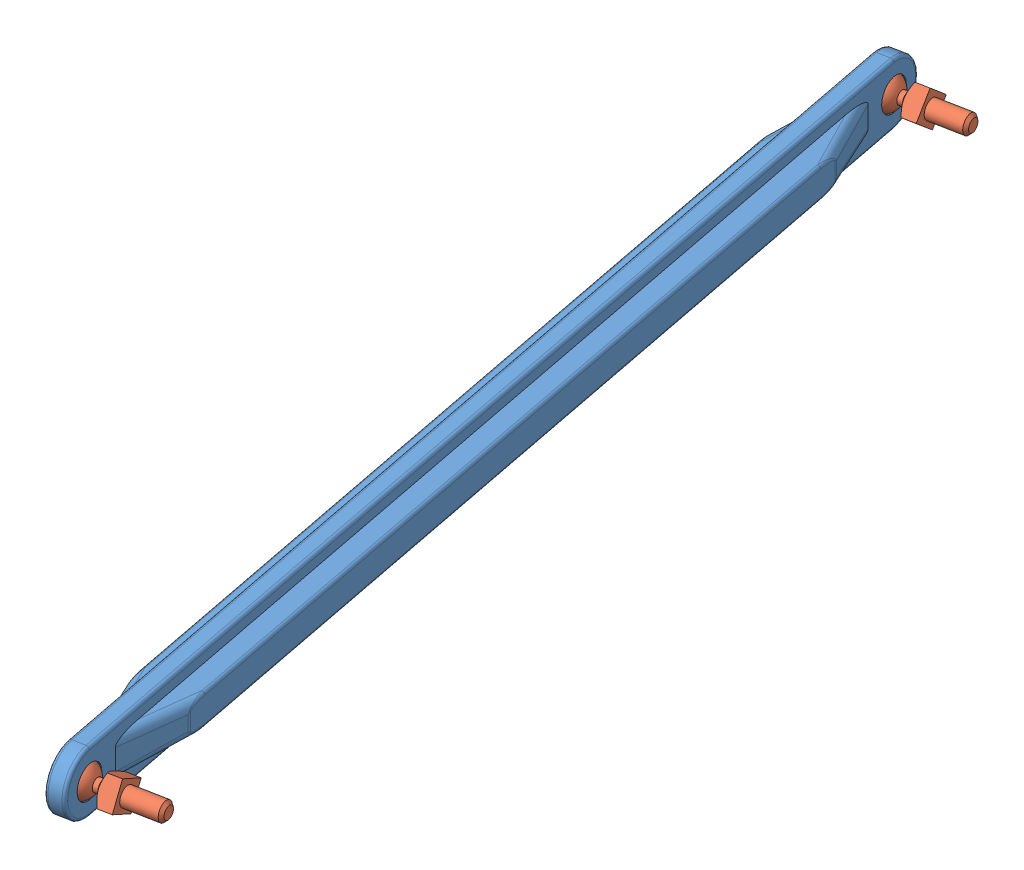
SolidWorks assembly Biellette_2.1, configuration Défaut. Lengths in mm.
Overall size (51.75 10.2 179.4).
3 component instances, 2 part files, 7 mates.
Components (placement in the parent):
- Biellette-1: Biellette [Défaut] at (-37.9316 0.1404 -150.7157) x (-0.981797 0 0.189933) z (0.189933 0 0.981797) size (10.49 10.2 180.2)
- Boule_biellette_v2-1: Boule_biellette_v2 [Défaut] at (-5.8167 0.1404 16.2234) x (0.981797 0 -0.189933) z (-0.091178 0.877239 -0.471316) size (15.93 5.86 5.86)
- Boule_biellette_v2-2: Boule_biellette_v2 [Défaut] at (-38.1053 0.1404 -150.6821) x (0.981797 0 -0.189933) z (-0.123862 0.758102 -0.640265) size (15.93 5.86 5.86)
Mates (geometry in assembly coordinates):
- Coaxiale9: concentric: sphere of Boule_biellette_v2-1; cylinder of Biellette-1 through (-1.225 0.1404 15.3351) axis (-0.981797 0 0.189933) radius 2.6142
- Coaxiale10: concentric: cylinder of Biellette-1 through (-33.5135 0.1404 -151.5704) axis (-0.981797 0 0.189933) radius 2.6142; sphere of Boule_biellette_v2-2
- Tangent14: tangent: circle of Biellette-1; sphere of Boule_biellette_v2-2
- Tangent19: tangent: sphere of Boule_biellette_v2-1; circle of Biellette-1
- Parallèle1: parallel aligned: plane of Biellette-1 through (-3.2017 4.7404 20.9121) normal (0.981797 0 -0.189933); plane of Boule_biellette_v2-1 through (0.4727 -1.5398 11.8794) normal (0.981797 0 -0.189933)
- Parallèle4: parallel aligned: plane of Biellette-1 through (-3.2017 4.7404 20.9121) normal (0.981797 0 -0.189933); plane of Boule_biellette_v2-2 through (-25.5579 -0.8378 -154.2677) normal (0.981797 0 -0.189933)
- Coïncidente8: coincident aligned: plane of Boule_biellette_v2-1 through (0.4727 -1.5398 11.8794) normal (0.981797 0 -0.189933); plane of Boule_biellette_v2-2 through (-31.7367 -2.1421 -154.6167) normal (0.981797 0 -0.189933)
